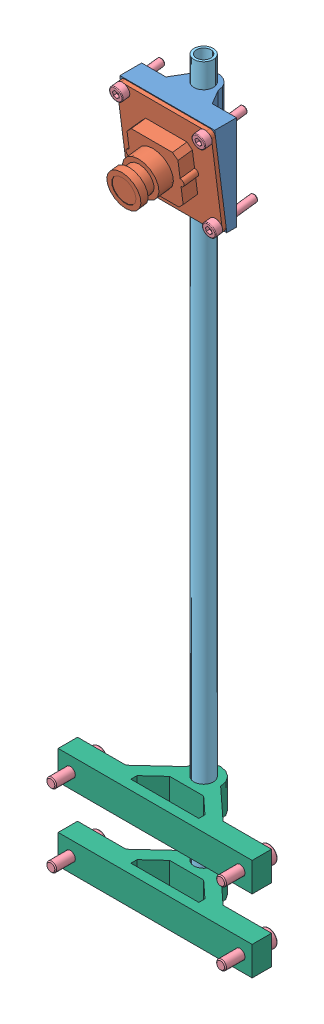
SolidWorks assembly СборкаКамеры, configuration По умолчанию. Lengths in mm.
Overall size (80 300 42.39).
14 component instances, 6 part files, 18 mates.
Components (placement in the parent):
- Держатель камеры-1: Держатель камеры [По умолчанию] at origin size (39.1 39.1 21)
- Innomaker_OV9281-1: Innomaker_OV9281 [По умолчанию] at (0 19.3921 12.4798) x (1 0 0) z (0 -0.991923 -0.126844) size (39.1 23.4 39.1)
- втулкаПодКамеру-1: втулкаПодКамеру [По умолчанию] at (-17 36.5085 12.6523) x (0.999968 -0.007874 -0.001007) z (0 -0.126844 0.991923) size (5 5 2)
- socket head cap screw_din-1: socket head cap screw_din [DIN 912 M3 x 16 --- 16N] at (-17 35.6713 19.199) x (0 0.126844 -0.991923) z (-0.981761 -0.188585 -0.024116) size (19 5.5 5.5)
- труба-1: труба [По умолчанию] at (0 -250.9 0) x (0.868597 0 -0.49552) z (0.49552 0 0.868597) size (8 300 8)
- кронштейн-1: кронштейн [По умолчанию] at (0 -250.9 0) size (80 12 27)
- кронштейн-2: кронштейн [По умолчанию] at (0 -220.9 0) size (80 12 27)
- socket head cap screw_din-5: socket head cap screw_din [DIN 912 M3 x 16 --- 16N] at (-17 1.9459 14.8863) x (0 0.126844 -0.991923) z (-0.981761 -0.188585 -0.024116) size (19 5.5 5.5)
- socket head cap screw_din-6: socket head cap screw_din [DIN 912 M3 x 16 --- 16N] at (17 35.6713 19.199) x (0 0.126844 -0.991923) z (-0.981761 -0.188585 -0.024116) size (19 5.5 5.5)
- socket head cap screw_din-7: socket head cap screw_din [DIN 912 M3 x 16 --- 16N] at (17 1.9459 14.8863) x (0 0.126844 -0.991923) z (-0.981761 -0.188585 -0.024116) size (19 5.5 5.5)
- socket head cap screw_din-8: socket head cap screw_din [DIN 912 M4 x 16 --- 16N] at (35 -214.9 8) x (0 0 1) z (-1 0 0) size (20 7 7)
- socket head cap screw_din-9: socket head cap screw_din [DIN 912 M4 x 16 --- 16N] at (35 -244.9 8) x (0 0 1) z (-1 0 0) size (20 7 7)
- socket head cap screw_din-10: socket head cap screw_din [DIN 912 M4 x 16 --- 16N] at (-35 -214.9 8) x (0 0 1) z (-1 0 0) size (20 7 7)
- socket head cap screw_din-11: socket head cap screw_din [DIN 912 M4 x 16 --- 16N] at (-35 -244.9 8) x (0 0 1) z (-1 0 0) size (20 7 7)
Mates (geometry in assembly coordinates):
- Концентричный17: concentric anti-aligned: cylinder of Innomaker_OV9281-1 through (-17 36.2548 14.6362) axis (0 -0.126844 0.991923) radius 1.5; cylinder of втулкаПодКамеру-1 through (-17 36.2548 14.6362) axis (0 0.126844 -0.991923) radius 1.5
- Совпадение13: coincident anti-aligned: plane of Innomaker_OV9281-1 through (0 19.3921 12.4798) normal (0 0.126844 -0.991923); plane of втулкаПодКамеру-1 through (-17 36.2548 14.6362) normal (0 -0.126844 0.991923)
- Концентричный18: concentric aligned: cylinder of Innomaker_OV9281-1 through (-17 36.2548 14.6362) axis (0 -0.126844 0.991923) radius 1.5; cylinder of socket head cap screw_din-1 through (-17 31.644 50.6925) axis (0 -0.126844 0.991923) radius 1.5
- Совпадение14: coincident anti-aligned: plane of Innomaker_OV9281-1 through (0 19.1891 14.0669) normal (0 -0.126844 0.991923); plane of socket head cap screw_din-1 through (-16.4772 33.3738 15.8808) normal (0 0.126844 -0.991923)
- Концентричный19: concentric aligned: cylinder of socket head cap screw_din-1 through (-17 31.644 50.6925) axis (0 -0.126844 0.991923) radius 1.5; cylinder of ? through (-17 38.5307 -3.1614) axis (0 -0.126844 0.991923) radius 1.25
- Совпадение15: coincident anti-aligned: plane of Держатель камеры-1 through (-19.55 0 10) normal (0 -0.126844 0.991923); plane of Innomaker_OV9281-1 through (0 19.3921 12.4798) normal (0 0.126844 -0.991923)
- Концентричный20: concentric aligned: cylinder of Держатель камеры-1 through (-17 2.5294 10.3235) axis (0 -0.126844 0.991923) radius 1.575; cylinder of Innomaker_OV9281-1 through (-17 2.5294 10.3235) axis (0 -0.126844 0.991923) radius 1.5
- Концентричный21: concentric aligned: cylinder of Держатель камеры-1 through (17 36.2548 14.6362) axis (0 -0.126844 0.991923) radius 1.575; cylinder of Innomaker_OV9281-1 through (17 36.2548 14.6362) axis (0 -0.126844 0.991923) radius 1.5
- Концентричный22: concentric aligned: cylinder of Держатель камеры-1 through (0 39.1 0) axis (0 -1 0) radius 4; cylinder of труба-1 through (0 49.1 0) axis (0 -1 0) radius 4
- Расстояние3: distance = 10 mm aligned: plane of Держатель камеры-1 through (0 39.1 0) normal (0 1 0); plane of труба-1 through (0 49.1 0) normal (0 1 0)
- Концентричный23: concentric aligned: cylinder of труба-1 through (0 49.1 0) axis (0 -1 0) radius 4; cylinder of кронштейн-1 through (0 -238.9 0) axis (0 -1 0) radius 4
- Совпадение18: coincident aligned: plane of труба-1 through (0 -250.9 0) normal (0 -1 0); plane of кронштейн-1 through (0 -250.9 0) normal (0 -1 0)
- Параллельность6: parallel aligned: plane of Держатель камеры-1 through (-19.55 39.1 10) normal (-1 0 0); plane of кронштейн-1 through (-40 -238.9 20) normal (-1 0 0)
- Концентричный24: concentric aligned: cylinder of труба-1 through (0 49.1 0) axis (0 -1 0) radius 4; cylinder of кронштейн-2 through (0 -208.9 0) axis (0 -1 0) radius 4
- Параллельность7: parallel aligned: plane of Держатель камеры-1 through (-19.55 39.1 10) normal (-1 0 0); plane of кронштейн-2 through (-40 -208.9 20) normal (-1 0 0)
- Расстояние4: distance = 30 mm aligned: plane of кронштейн-2 through (0 -220.9 0) normal (0 -1 0); plane of кронштейн-1 through (0 -250.9 0) normal (0 -1 0)
- Концентричный25: concentric anti-aligned: cylinder of кронштейн-2 through (35 -214.9 20) axis (0 0 1) radius 2.1; cylinder of socket head cap screw_din-8 through (35 -214.9 -23.75) axis (0 0 -1) radius 2
- Совпадение24: coincident anti-aligned: plane of кронштейн-2 through (40 -208.9 12) normal (0 0 -1); plane of socket head cap screw_din-8 through (35 -211.4 12) normal (0 0 1)
